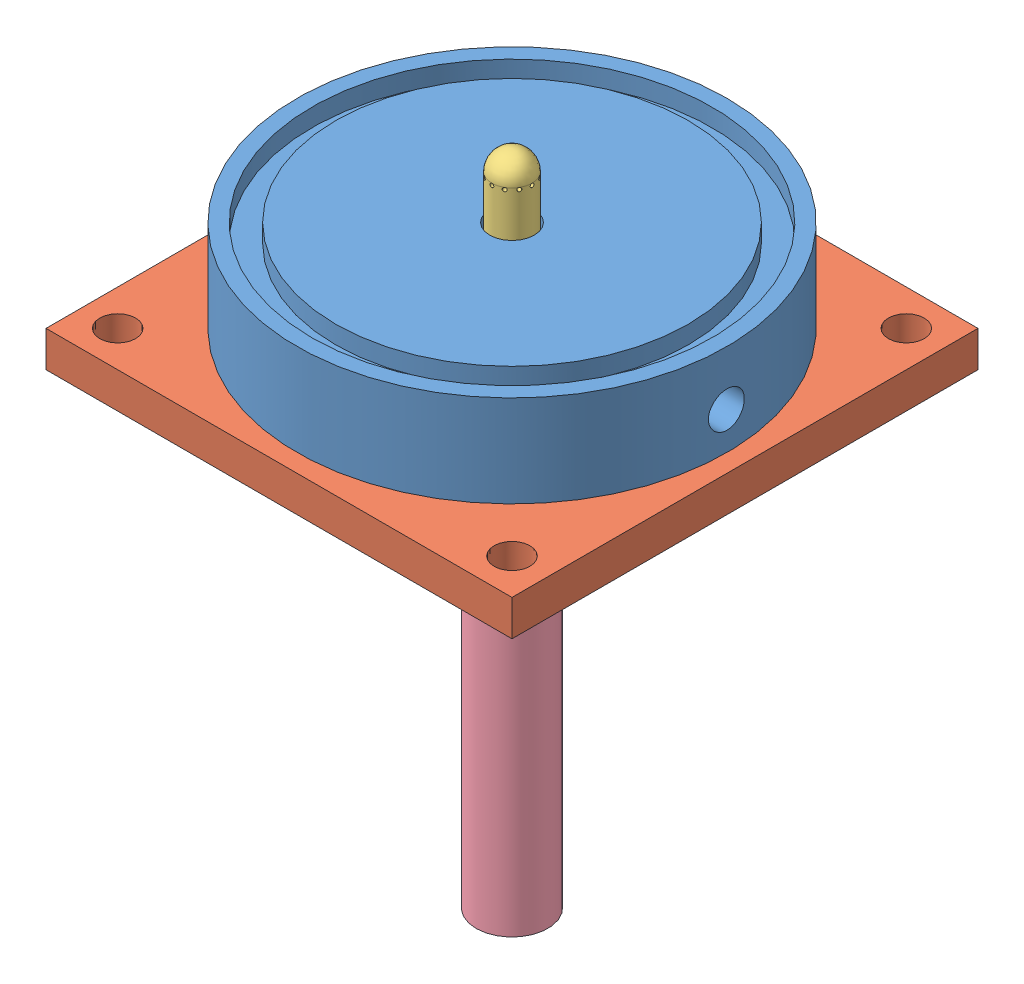
SolidWorks assembly Assembly_Cold_Test, configuration Default. Lengths in mm.
Overall size (82.55 116.52 82.55).
4 component instances, 4 part files, 6 mates.
Components (placement in the parent):
- Part_Cold_Test_Annulus_V1-1: Part_Cold_Test_Annulus_V1 [Default] at origin size (76.2 16.26 76.2)
- Part_Cold_Test_Plate_V1-2: Part_Cold_Test_Plate_V1 [Default] at (0 -8.8214 0) x (1 0 0) z (0 0 -1) size (82.55 6.35 82.55)
- Part_Pintle_V1-2: Part_Pintle_V1 [Default] at (0 14.2574 0) x (1 0 0) z (0 0 -1) size (35.56 53.02 35.56)
- Part_SSTube-1: Part_SSTube [Default] at (0 -97.7214 0) size (12.7 76.2 12.7)
Mates (geometry in assembly coordinates):
- Concentric2: concentric: circle of Part_Cold_Test_Annulus_V1-1; circle of Part_Cold_Test_Plate_V1-2
- Coincident2: coincident: plane of Part_Cold_Test_Annulus_V1-1 through (22.6695 -8.8214 0) normal (0 -1 0); plane of Part_Cold_Test_Plate_V1-2 through (0 -8.8214 0) normal (0 1 0)
- Concentric3: concentric: circle of Part_Cold_Test_Plate_V1-2; circle of Part_Pintle_V1-2
- Coincident3: coincident: plane of Part_Cold_Test_Plate_V1-2 through (0 -15.1714 0) normal (0 -1 0); plane of Part_Pintle_V1-2 through (0 -15.1714 0) normal (0 1 0)
- Concentric4: concentric: circle of Part_Pintle_V1-2; circle of Part_SSTube-1
- Coincident4: coincident: plane of Part_Pintle_V1-2 through (0 -21.5214 0) normal (0 -1 0); plane of Part_SSTube-1 through (0 -21.5214 0) normal (0 1 0)
